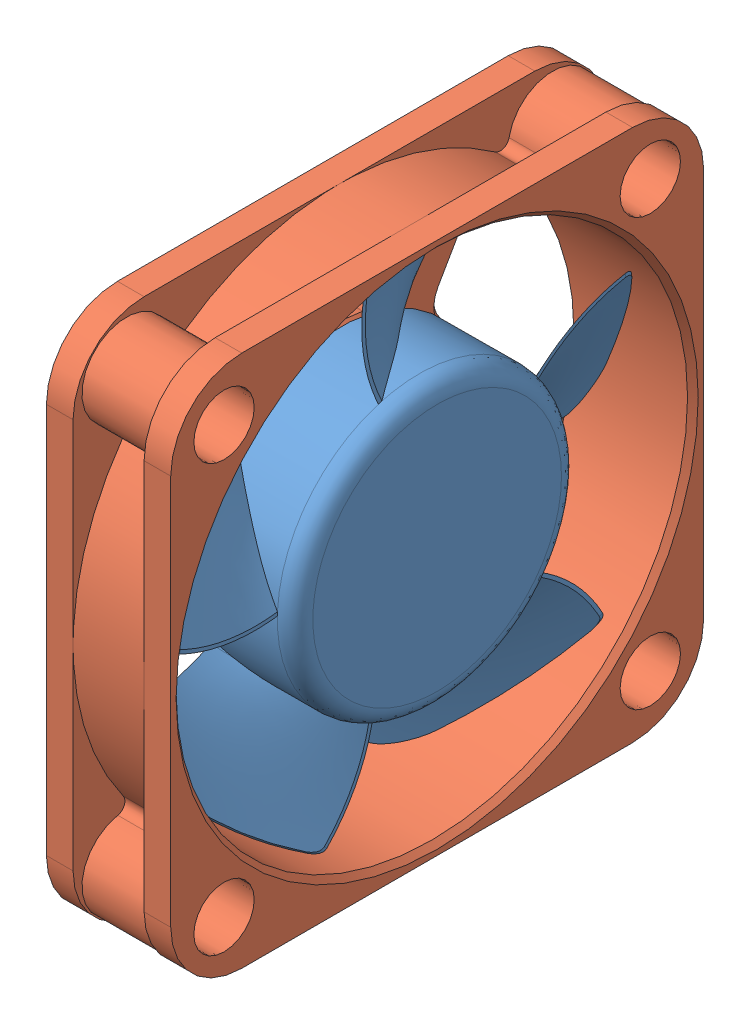
SolidWorks assembly fan-30mm, configuration Default. Lengths in mm.
Overall size (7 30 30).
3 component instances, 2 part files, 0 mates.
Components (placement in the parent):
- Fan 30mm(2)^fan-30mm-1: Fan 30mm(2)^fan-30mm [Default] at origin size (7 30 30) (virtual)
  - Component1^Fan 30mm(2)_fan-30mm-1: Component1^Fan 30mm(2)_fan-30mm [Default] at (1.5 0 0) size (5.55 27.93 28.14) (virtual)
  - Fan 30mm(2)^Fan 30mm(2)_fan-30mm-1: Fan 30mm(2)^Fan 30mm(2)_fan-30mm [Default] at origin size (7 30 30) (virtual)
